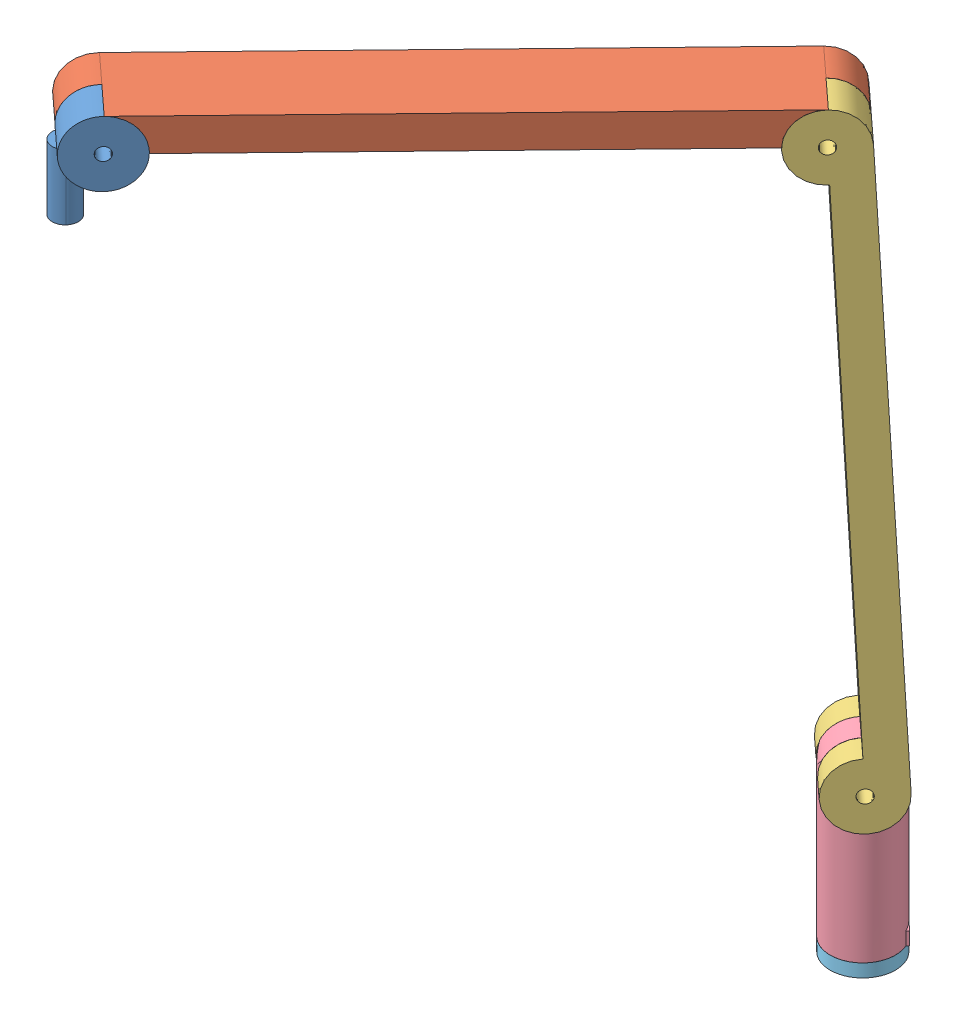
SolidWorks assembly Mic-Halter, configuration Standard. Lengths in mm.
Overall size (358.72 588.43 386.35).
5 component instances, 5 part files, 16 mates.
Components (placement in the parent):
- Mic-Arm-Kopf-1: Mic-Arm-Kopf [Standard] at (-260.426 562.9638 369.9979) x (0 -1 0) z (-0.736464 0 -0.676476) size (75 55 30)
- Mic-Arm-Oberarm-1: Mic-Arm-Oberarm [Standard] at (-282.52 562.9638 349.7037) x (-0.676355 0.018947 0.736332) z (-0.736464 0 -0.676476) size (443 50 60)
- Mic-Arm-Unterarm-1: Mic-Arm-Unterarm [Standard] at (-16.7125 555.5176 60.3251) x (-0.031959 0.998883 0.034793) z (-0.736464 0 -0.676476) size (482 50 60)
- Mic-Arm-Fuß-1: Mic-Arm-Fuß [Standard] at (-2.9061 124 45.2943) x (0 -1 0) z (-0.736464 0 -0.676476) size (139 50 50)
- Mic-Arm-Fuß-Boden-1: Mic-Arm-Fuß-Boden [Standard] at (-25 0 25) x (0 1 0) z (1 0 0) size (10 50 50)
Mates (geometry in assembly coordinates):
- Deckungsgleich1: coincident anti-aligned: plane of Mic-Arm-Oberarm-1 through (-304.6139 562.9638 329.4094) normal (0.736464 0 0.676476); plane of Mic-Arm-Kopf-1 through (-304.6139 562.9638 329.4094) normal (-0.736464 0 -0.676476)
- Konzentrisch1: concentric aligned: cylinder of Mic-Arm-Oberarm-1 through (-326.7078 562.9638 309.1151) axis (0.736464 0 0.676476) radius 5; cylinder of Mic-Arm-Kopf-1 through (-304.6139 562.9638 329.4094) axis (0.736464 0 0.676476) radius 5
- Deckungsgleich2: coincident anti-aligned: plane of Mic-Arm-Oberarm-1 through (-38.8065 555.5176 40.0308) normal (0.736464 0 0.676476); plane of Mic-Arm-Unterarm-1 through (-38.8065 555.5176 40.0308) normal (-0.736464 0 -0.676476)
- Konzentrisch2: concentric aligned: cylinder of Mic-Arm-Oberarm-1 through (-60.9004 555.5176 19.7365) axis (0.736464 0 0.676476) radius 5; cylinder of Mic-Arm-Unterarm-1 through (-60.9004 555.5176 19.7365) axis (0.736464 0 0.676476) radius 5
- Konzentrisch3: concentric aligned: cylinder of Mic-Arm-Unterarm-1 through (-47.0939 124 4.7057) axis (0.736464 0 0.676476) radius 5; cylinder of Mic-Arm-Fuß-1 through (-47.0939 124 4.7057) axis (0.736464 0 0.676476) radius 5
- Deckungsgleich7: coincident anti-aligned: plane of Mic-Arm-Fuß-Boden-1 through (-25 0 25) normal (0 -1 0); plane of assembly through (0 0 0) normal (0 1 0)
- Deckungsgleich8: coincident anti-aligned: plane of Mic-Arm-Fuß-Boden-1 through (-15 0 0) normal (0 0 -1); plane of assembly through (0 0 0) normal (0 0 1)
- Tangential1: tangent aligned: cylinder of Mic-Arm-Fuß-Boden-1 through (-25 10 25) axis (0 -1 0) radius 25; plane of assembly through (0 0 0) normal (1 0 0)
- Deckungsgleich9: coincident aligned: line of Mic-Arm-Fuß-1 through (-25 134 25) axis (0 -1 0); line of Mic-Arm-Fuß-Boden-1 through (-25 10 25) axis (0 -1 0)
- Deckungsgleich10: coincident anti-aligned: plane of Mic-Arm-Fuß-1 through (-64.0058 10 23.1173) normal (0 -1 0); plane of Mic-Arm-Fuß-Boden-1 through (-25 10 25) normal (0 1 0)
- LimitWinkel1: limit planar angle = 3.88456 rad anti-aligned: plane of Mic-Arm-Fuß-Boden-1 through (-15 0 0) normal (0 0 -1); plane of Mic-Arm-Fuß-1 through (-0.7234 20 13.3532) normal (0.676476 0 -0.736464)
- Deckungsgleich12: coincident anti-aligned: plane of Mic-Arm-Unterarm-1 through (-32.3646 124 18.2352) normal (0.736464 0 0.676476); plane of Mic-Arm-Fuß-1 through (-32.3646 124 18.2352) normal (-0.736464 0 -0.676476)
- LimitWinkel2: limit planar angle = 3.188854 rad anti-aligned: plane of Mic-Arm-Unterarm-1 through (-44.0074 556.6987 1.3454) normal (0.675721 0.047244 -0.735642); plane of Mic-Arm-Fuß-1 through (-0.7234 20 13.3532) normal (0.676476 0 -0.736464)
- LimitWinkel3: limit planar angle = 1.637006 rad anti-aligned: plane of Mic-Arm-Oberarm-1 through (-326.3874 587.9593 308.7662) normal (0.012817 0.99982 -0.013954); plane of Mic-Arm-Unterarm-1 through (-44.0074 556.6987 1.3454) normal (0.675721 0.047244 -0.735642)
- LimitWinkel4: limit planar angle = 3.160541 rad anti-aligned: plane of Mic-Arm-Kopf-1 through (-321.5258 562.9638 347.821) normal (0 1 0); plane of Mic-Arm-Oberarm-1 through (-326.3874 587.9593 308.7662) normal (0.012817 0.99982 -0.013954)
- Parallel2: parallel aligned: plane of Mic-Arm-Kopf-1 through (-324.9082 512.9638 351.5033) normal (0 -1 0); plane of Mic-Arm-Fuß-Boden-1 through (-25 0 25) normal (0 -1 0)
